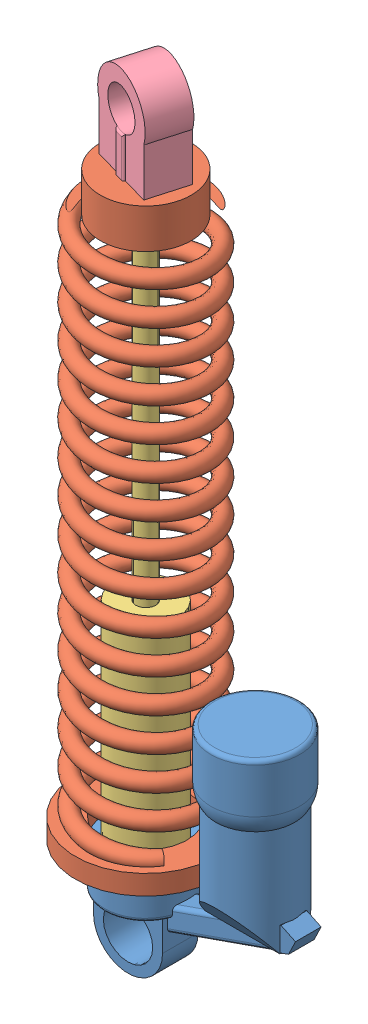
SolidWorks assembly coil suspension, configuration Default. Lengths in mm.
Overall size (131.95 395.98 99.5).
4 component instances, 4 part files, 5 mates.
Components (placement in the parent):
- shock absorber-1: shock absorber [Default] at (85.2984 57.0096 91.0381) size (103.34 132.5 45)
- spring-1: spring [Default] at (85.2984 89.0096 91.0381) x (-0.837525 0 -0.546399) z (0.546399 0 -0.837525) size (71.32 294 72.28)
- middle rod-1: middle rod [Default] at (85.2984 324.0096 91.0381) x (0.961474 0 0.274896) z (0 -1 0) size (32 32 290)
- spnsn part 3-1: spnsn part 3 [Default] at (82.5521 402.9857 100.6536) x (0.961551 0 0.274625) z (0.274625 0 -0.961551) size (42 60.33 42)
Mates (geometry in assembly coordinates):
- Concentric1: concentric aligned: circle of shock absorber-1; circle of spring-1
- Concentric2: concentric aligned: circle of middle rod-1; circle of spnsn part 3-1
- Coincident6: coincident anti-aligned: plane of shock absorber-1 through (85.2984 79.0096 91.0381) normal (0 1 0); plane of spring-1 through (85.2984 79.0096 91.0381) normal (0 -1 0)
- Concentric3: concentric anti-aligned: circle of shock absorber-1; circle of middle rod-1
- Coincident9: coincident anti-aligned: plane of shock absorber-1 through (85.2984 64.0096 91.0381) normal (0 1 0); plane of middle rod-1 through (85.2984 64.0096 91.0381) normal (0 -1 0)
